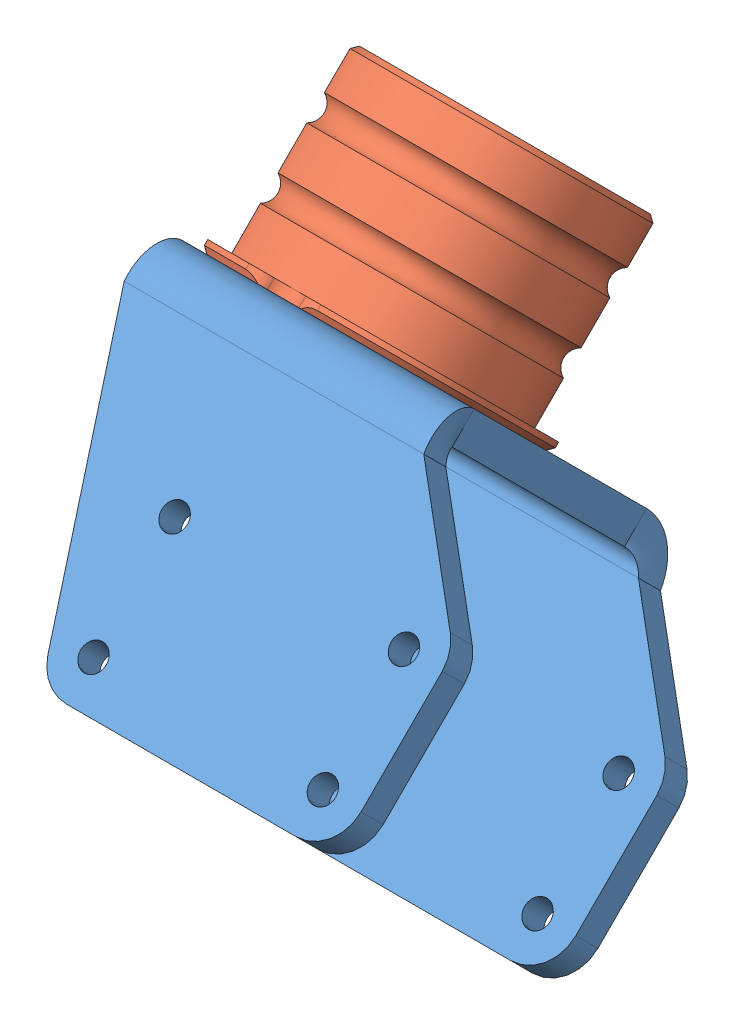
SolidWorks assembly J4 Sim, configuration Default. Lengths in mm.
Overall size (50.25 320.38 548.3).
2 component instances, 2 part files, 3 mates.
Components (placement in the parent):
- J4_Mount-1: J4_Mount [Default] at origin size (50.25 320.38 548.3)
- Glue_In_Plug-1: Glue_In_Plug [Default] at (0 33.6436 319.9098) x (1 0 0) z (0 0.967987 0.251) size (30 30.09 33.22)
Mates (geometry in assembly coordinates):
- Coincident1: coincident anti-aligned: plane of J4_Mount-1 through (0 60.988 292.5654) normal (0 0.707107 -0.707107); plane of Glue_In_Plug-1 through (0 56.0382 287.6157) normal (0 -0.707107 0.707107)
- Concentric1: concentric aligned: cylinder of J4_Mount-1 through (0 65.751 301.9445) axis (0 -0.707107 0.707107) radius 1.35; cylinder of Glue_In_Plug-1 through (0 68.059 299.6365) axis (0 -0.707107 0.707107) radius 1.25
- Concentric2: concentric aligned: cylinder of J4_Mount-1 through (7.0711 63.68 299.8734) axis (0 -0.707107 0.707107) radius 1.35; cylinder of Glue_In_Plug-1 through (7.0711 65.988 297.5654) axis (0 -0.707107 0.707107) radius 1.25
